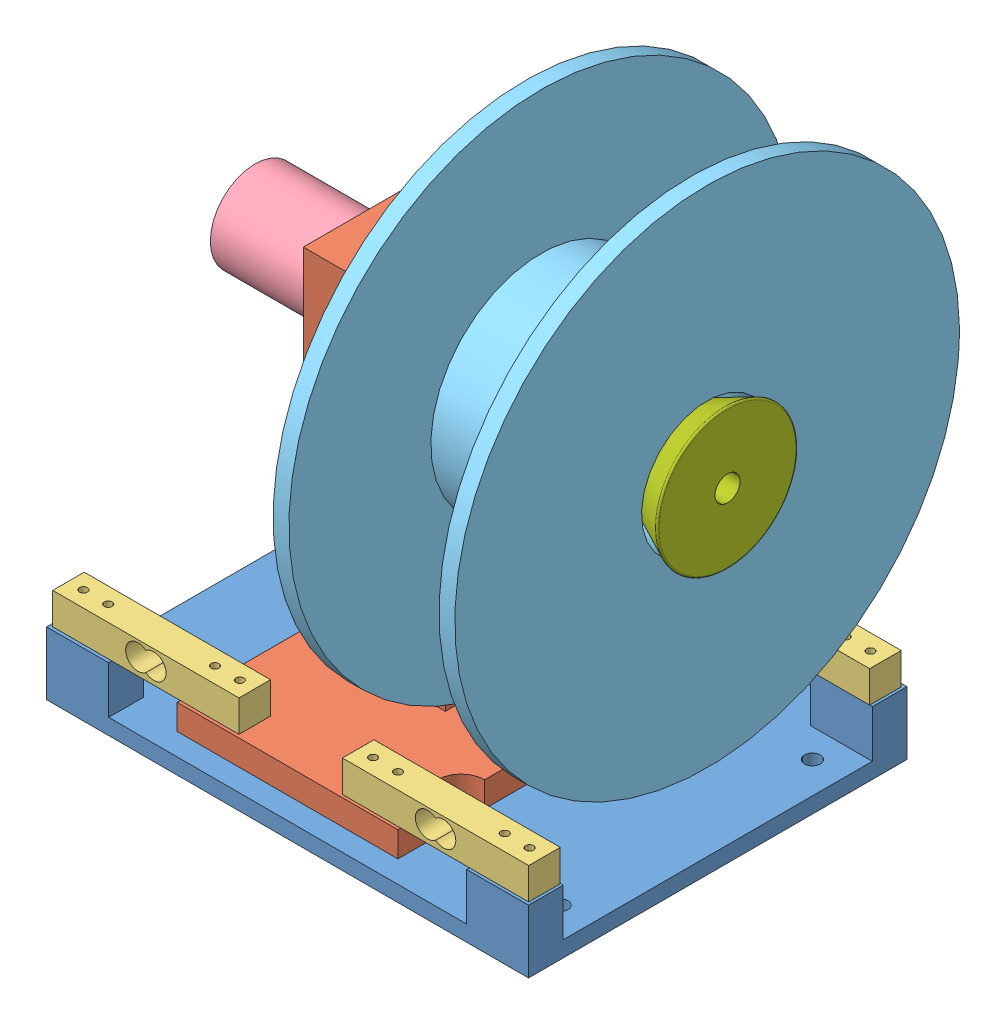
SolidWorks assembly SpoolerAssem, configuration Default. Lengths in mm.
Overall size (197.99 240.79 212.35).
10 component instances, 7 part files, 21 mates.
Components (placement in the parent):
- BaseMountingPlateSpooler-1: BaseMountingPlateSpooler [Default] at origin size (194.06 25.4 152.4)
- TopPlateSpooler-1: TopPlateSpooler [Default] at (-52.578 15.24 0) size (88.9 143.51 152.4)
- StrainGauge-1: StrainGauge [Default] at (3.4875 25.4 88.5367) size (75 12.7 12.7)
- StrainGauge-2: StrainGauge [Default] at (3.4835 25.4 -48.7433) size (75 12.7 12.7)
- StrainGauge-3: StrainGauge [Default] at (-90.7515 25.4 87.9722) x (-1 0 0) z (0 0 -1) size (75 12.7 12.7)
- StrainGauge-4: StrainGauge [Default] at (-90.8635 25.4 -49.3078) x (-1 0 0) z (0 0 -1) size (75 12.7 12.7)
- Spooler servo-1: Spooler servo [Default] at (-132.988 134.62 19.6144) size (121 36 36)
- 1kg_Spool-1: 1kg_Spool [Default] at (-24.1036 134.62 19.6144) x (0 -0.046086 -0.998937) z (1 0 0) size (203.2 203.2 73.15)
- SpoolCrusher-1: SpoolCrusher [Default] at (-30.988 134.62 19.6144) x (0 0 -1) z (1 0 0) size (56.43 56.43 25.4)
- SpoolCrusherEnd-1: SpoolCrusherEnd [Default] at (57.2712 134.62 19.6144) x (0 -0.063896 0.997957) z (-1 0 0) size (56.43 56.43 25.4)
Mates (geometry in assembly coordinates):
- Coincident2: coincident anti-aligned: plane of TopPlateSpooler-1 through (-52.578 25.4 0) normal (0 1 0); plane of StrainGauge-1 through (3.4875 25.4 88.5367) normal (0 -1 0)
- Coincident3: coincident aligned: plane of BaseMountingPlateSpooler-1 through (-140.716 6.35 -56.5856) normal (0 0 -1); plane of TopPlateSpooler-1 through (-88.138 25.4 -56.5856) normal (0 0 -1)
- Concentric3: concentric aligned: cylinder of TopPlateSpooler-1 through (-16.738 15.24 88.3144) axis (0 1 0) radius 2.5; cylinder of StrainGauge-1 through (-16.738 25.4 88.3144) axis (0 1 0) radius 1.6
- Width1: width aligned: plane of BaseMountingPlateSpooler-1 through (53.34 6.35 -56.5856) normal (1 0 0); plane of BaseMountingPlateSpooler-1 through (-140.716 6.35 -56.5856) normal (-1 0 0); plane of TopPlateSpooler-1 through (0.762 25.4 -56.5856) normal (1 0 0); plane of TopPlateSpooler-1 through (-88.138 25.4 -56.5856) normal (-1 0 0)
- Coincident4: coincident anti-aligned: plane of BaseMountingPlateSpooler-1 through (0 25.4 0) normal (0 1 0); plane of StrainGauge-2 through (3.4835 25.4 -48.7433) normal (0 -1 0)
- Concentric7: concentric aligned: cylinder of BaseMountingPlateSpooler-1 through (36.258 0 -48.9656) axis (0 1 0) radius 2.5; cylinder of StrainGauge-2 through (36.258 25.4 -48.9656) axis (0 1 0) radius 1.6
- Concentric9: concentric aligned: cylinder of BaseMountingPlateSpooler-1 through (-123.526 0 88.1944) axis (0 1 0) radius 2.5; cylinder of StrainGauge-3 through (-123.526 25.4 88.1944) axis (0 1 0) radius 1.6
- Coincident5: coincident anti-aligned: plane of TopPlateSpooler-1 through (-52.578 25.4 0) normal (0 1 0); plane of StrainGauge-3 through (-90.7515 25.4 87.9722) normal (0 -1 0)
- Concentric10: concentric aligned: cylinder of TopPlateSpooler-1 through (-80.638 15.24 -49.0856) axis (0 1 0) radius 2.5; cylinder of StrainGauge-4 through (-80.638 25.4 -49.0856) axis (0 1 0) radius 1.6
- Concentric11: concentric aligned: cylinder of TopPlateSpooler-1 through (-70.638 15.24 -49.0856) axis (0 1 0) radius 2.5; cylinder of StrainGauge-4 through (-70.638 25.4 -49.0856) axis (0 1 0) radius 1.6
- Coincident6: coincident anti-aligned: plane of BaseMountingPlateSpooler-1 through (0 25.4 0) normal (0 1 0); plane of StrainGauge-4 through (-90.8635 25.4 -49.3078) normal (0 -1 0)
- Concentric13: concentric aligned: cylinder of TopPlateSpooler-1 through (-6.738 15.24 88.3144) axis (0 1 0) radius 2.5; cylinder of StrainGauge-1 through (-6.738 25.4 88.3144) axis (0 1 0) radius 1.6
- Coincident7: coincident anti-aligned: plane of TopPlateSpooler-1 through (-52.578 25.4 0) normal (0 1 0); plane of StrainGauge-2 through (3.4835 25.4 -48.7433) normal (0 -1 0)
- Concentric14: concentric aligned: cylinder of TopPlateSpooler-1 through (-33.988 134.62 19.6144) axis (-1 0 0) radius 16.5; cylinder of Spooler servo-1 through (-33.988 134.62 19.6144) axis (-1 0 0) radius 16
- Coincident9: coincident anti-aligned: plane of TopPlateSpooler-1 through (-33.988 134.62 19.6144) normal (-1 0 0); plane of Spooler servo-1 through (-33.988 134.62 19.6144) normal (1 0 0)
- Concentric15: concentric aligned: cylinder of Spooler servo-1 through (-14.988 134.62 19.6144) axis (-1 0 0) radius 3; cylinder of SpoolCrusher-1 through (-15.738 134.62 19.6144) axis (-1 0 0) radius 3.125
- Parallel1: parallel anti-aligned: plane of Spooler servo-1 through (-14.988 137.12 21.2728) normal (0 1 0); plane of SpoolCrusher-1 through (-15.738 136.97 17.5546) normal (0 -1 0)
- Parallel2: parallel aligned: plane of TopPlateSpooler-1 through (-88.138 158.75 -5.7856) normal (0 0 -1); plane of Spooler servo-1 through (-30.988 138.9789 10.6144) normal (0 0 -1)
- Coincident12: coincident anti-aligned: plane of TopPlateSpooler-1 through (-30.988 158.75 45.0144) normal (1 0 0); plane of SpoolCrusher-1 through (-30.988 134.62 19.6144) normal (-1 0 0)
- Concentric16: concentric anti-aligned: circle of Spooler servo-1; circle of SpoolCrusherEnd-1
- Concentric17: concentric anti-aligned: circle of Spooler servo-1; circle of 1kg_Spool-1
